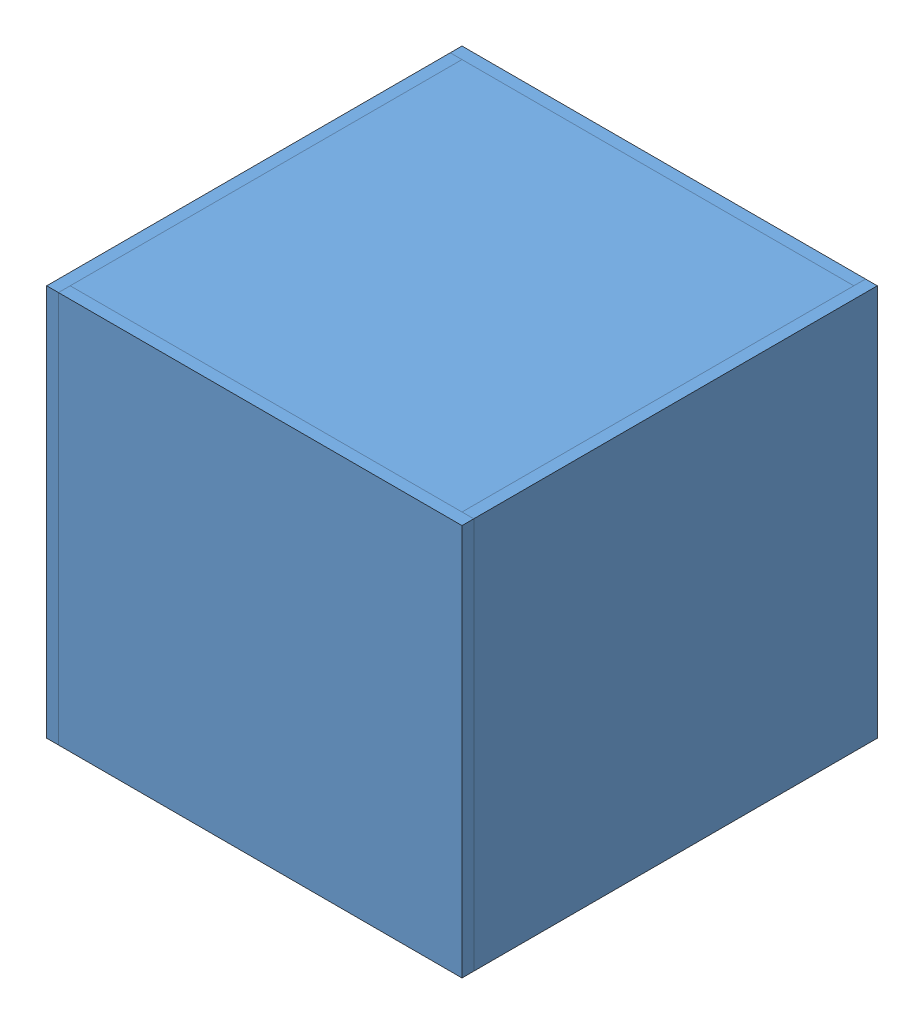
SolidWorks assembly Cube, configuration Default. Lengths in mm.
Overall size (106 102.84 106).
19 component instances, 4 part files, 40 mates.
Components (placement in the parent):
- Side.SLDPART-1: Side.SLDPART [Default] at (47.5053 44.4582 76.6376) size (100 3 100)
- Arduino-1: Arduino [Default] at (41.5053 60.1582 92.4876) size (74.8 12.1 53.3)
- 25x.5 Aluminum Hex Female Female Standoff-1: 25x.5 Aluminum Hex Female Female Standoff [Default] at (22.5053 53.8082 116.6376) x (0.377672 0 -0.92594) z (0 -1 0) size (6.35 8.06 12.7)
- 25x.5 Aluminum Hex Female Female Standoff-2: 25x.5 Aluminum Hex Female Female Standoff [Default] at (74.9053 53.8082 83.6376) x (1 0 0) z (0 -1 0) size (6.35 8.06 12.7)
- 25x.5 Aluminum Hex Female Female Standoff-3: 25x.5 Aluminum Hex Female Female Standoff [Default] at (24.1053 53.8082 68.3376) x (0.24691 0 -0.969038) z (0 -1 0) size (6.35 8.06 12.7)
- 25x.5 Aluminum Hex Female Female Standoff-4: 25x.5 Aluminum Hex Female Female Standoff [Default] at (74.9053 53.8082 111.5376) x (1 0 0) z (0 -1 0) size (6.35 8.06 12.7)
- socket head cap screw_ai-2: socket head cap screw_ai [HX-SHCS 0.112-40x0.25x0.25-N] at (22.5053 64.603 116.6376) x (0 -1 0) z (0 0 1) size (9.19 4.65 4.65)
- socket head cap screw_ai-3: socket head cap screw_ai [HX-SHCS 0.112-40x0.25x0.25-N] at (74.9053 64.603 111.5376) x (0 -1 0) z (0 0 1) size (9.19 4.65 4.65)
- socket head cap screw_ai-4: socket head cap screw_ai [HX-SHCS 0.112-40x0.25x0.25-N] at (74.9053 64.603 83.6376) x (0 -1 0) z (0 0 1) size (9.19 4.65 4.65)
- socket head cap screw_ai-5: socket head cap screw_ai [HX-SHCS 0.112-40x0.25x0.25-N] at (24.1053 64.603 68.3376) x (0 -1 0) z (0 0 1) size (9.19 4.65 4.65)
- socket head cap screw_ai-6: socket head cap screw_ai [HX-SHCS 0.112-40x0.25x0.25-N] at (74.9053 41.6134 111.5376) x (0 1 0) z (0 0 1) size (9.19 4.65 4.65)
- socket head cap screw_ai-7: socket head cap screw_ai [HX-SHCS 0.112-40x0.25x0.25-N] at (74.9053 41.6134 83.6376) x (0 1 0) z (0 0 1) size (9.19 4.65 4.65)
- socket head cap screw_ai-8: socket head cap screw_ai [HX-SHCS 0.112-40x0.25x0.25-N] at (24.1053 41.6134 68.3376) x (0 1 0) z (0 0 1) size (9.19 4.65 4.65)
- socket head cap screw_ai-9: socket head cap screw_ai [HX-SHCS 0.112-40x0.25x0.25-N] at (22.5053 41.6134 116.6376) x (0 1 0) z (0 0 1) size (9.19 4.65 4.65)
- Side.SLDPART-4: Side.SLDPART [No Holes] at (49.0053 94.4582 129.6376) x (0 1 0) z (-1 0 0) size (100 3 103)
- Side.SLDPART-5: Side.SLDPART [No Holes] at (46.0053 94.4582 23.6376) x (0 1 0) z (1 0 0) size (100 3 103)
- Side.SLDPART-6: Side.SLDPART [No Holes] at (100.5053 94.4582 75.1376) x (0 1 0) z (0 0 1) size (100 3 103)
- Side.SLDPART-7: Side.SLDPART [No Holes] at (-5.4947 94.4582 78.1376) x (0 -1 0) z (0 0 1) size (100 3 103)
- Side.SLDPART-9: Side.SLDPART [No Holes Top] at (47.5053 141.4582 76.6376) size (100 3 100)
Mates (geometry in assembly coordinates):
- Concentric1: concentric anti-aligned: cylinder of Side.SLDPART-1 through (22.5053 44.4582 116.6376) axis (0 1 0) radius 1.6; cylinder of Arduino-1 through (22.5053 61.7582 116.6376) axis (0 -1 0) radius 1.6
- Concentric2: concentric anti-aligned: cylinder of Side.SLDPART-1 through (74.9053 44.4582 83.6376) axis (0 1 0) radius 1.6; cylinder of Arduino-1 through (74.9053 61.7582 83.6376) axis (0 -1 0) radius 1.6
- Concentric3: concentric anti-aligned: cylinder of Side.SLDPART-1 through (22.5053 44.4582 116.6376) axis (0 1 0) radius 1.6; cylinder of 25x.5 Aluminum Hex Female Female Standoff-1 through (22.5053 47.4582 116.6376) axis (0 -1 0) radius 1.0287
- Concentric4: concentric anti-aligned: cylinder of Side.SLDPART-1 through (74.9053 44.4582 111.5376) axis (0 1 0) radius 1.6; cylinder of 25x.5 Aluminum Hex Female Female Standoff-4 through (74.9053 47.4582 111.5376) axis (0 -1 0) radius 1.0287
- Concentric5: concentric anti-aligned: cylinder of Side.SLDPART-1 through (24.1053 44.4582 68.3376) axis (0 1 0) radius 1.6; cylinder of 25x.5 Aluminum Hex Female Female Standoff-3 through (24.1053 47.4582 68.3376) axis (0 -1 0) radius 1.0287
- Concentric6: concentric anti-aligned: cylinder of Side.SLDPART-1 through (74.9053 44.4582 83.6376) axis (0 1 0) radius 1.6; cylinder of 25x.5 Aluminum Hex Female Female Standoff-2 through (74.9053 47.4582 83.6376) axis (0 -1 0) radius 1.0287
- Coincident1: coincident anti-aligned: plane of Side.SLDPART-1 through (47.5053 47.4582 76.6376) normal (0 1 0); plane of 25x.5 Aluminum Hex Female Female Standoff-2 through (74.9053 47.4582 83.6376) normal (0 -1 0)
- Coincident2: coincident anti-aligned: plane of Side.SLDPART-1 through (47.5053 47.4582 76.6376) normal (0 1 0); plane of 25x.5 Aluminum Hex Female Female Standoff-4 through (74.9053 47.4582 111.5376) normal (0 -1 0)
- Coincident3: coincident anti-aligned: plane of Side.SLDPART-1 through (47.5053 47.4582 76.6376) normal (0 1 0); plane of 25x.5 Aluminum Hex Female Female Standoff-1 through (22.5053 47.4582 116.6376) normal (0 -1 0)
- Coincident4: coincident anti-aligned: plane of Side.SLDPART-1 through (47.5053 47.4582 76.6376) normal (0 1 0); plane of 25x.5 Aluminum Hex Female Female Standoff-3 through (24.1053 47.4582 68.3376) normal (0 -1 0)
- Coincident5: coincident anti-aligned: plane of Arduino-1 through (74.5053 60.1582 65.8376) normal (0 -1 0); plane of 25x.5 Aluminum Hex Female Female Standoff-1 through (22.5053 60.1582 116.6376) normal (0 1 0)
- Concentric7: concentric anti-aligned: cylinder of Arduino-1 through (22.5053 61.7582 116.6376) axis (0 -1 0) radius 1.6; cylinder of socket head cap screw_ai-2 through (22.5053 96.353 116.6376) axis (0 1 0) radius 2.3241
- Coincident6: coincident anti-aligned: plane of Arduino-1 through (74.5053 61.7582 65.8376) normal (0 1 0); plane of socket head cap screw_ai-2 through (24.8294 61.7582 116.6376) normal (0 -1 0)
- Concentric8: concentric anti-aligned: cylinder of Arduino-1 through (74.9053 61.7582 111.5376) axis (0 -1 0) radius 1.6; cylinder of socket head cap screw_ai-3 through (74.9053 96.353 111.5376) axis (0 1 0) radius 2.3241
- Coincident7: coincident anti-aligned: plane of Arduino-1 through (74.5053 61.7582 65.8376) normal (0 1 0); plane of socket head cap screw_ai-3 through (77.2294 61.7582 111.5376) normal (0 -1 0)
- Concentric9: concentric anti-aligned: cylinder of Arduino-1 through (74.9053 61.7582 83.6376) axis (0 -1 0) radius 1.6; cylinder of socket head cap screw_ai-4 through (74.9053 96.353 83.6376) axis (0 1 0) radius 2.3241
- Coincident8: coincident anti-aligned: plane of Arduino-1 through (74.5053 61.7582 65.8376) normal (0 1 0); plane of socket head cap screw_ai-4 through (77.2294 61.7582 83.6376) normal (0 -1 0)
- Concentric101: concentric anti-aligned: cylinder of Arduino-1 through (24.1053 61.7582 68.3376) axis (0 -1 0) radius 1.6; cylinder of socket head cap screw_ai-5 through (24.1053 96.353 68.3376) axis (0 1 0) radius 2.3241
- Coincident91: coincident anti-aligned: plane of Arduino-1 through (74.5053 61.7582 65.8376) normal (0 1 0); plane of socket head cap screw_ai-5 through (26.4294 61.7582 68.3376) normal (0 -1 0)
- Concentric11: concentric anti-aligned: cylinder of Side.SLDPART-1 through (74.9053 44.4582 111.5376) axis (0 1 0) radius 1.6; cylinder of socket head cap screw_ai-6 through (74.9053 9.8634 111.5376) axis (0 -1 0) radius 2.3241
- Coincident10: coincident anti-aligned: plane of Side.SLDPART-1 through (47.5053 44.4582 76.6376) normal (0 -1 0); plane of socket head cap screw_ai-6 through (72.5812 44.4582 111.5376) normal (0 1 0)
- Concentric12: concentric anti-aligned: cylinder of Side.SLDPART-1 through (74.9053 44.4582 83.6376) axis (0 1 0) radius 1.6; cylinder of socket head cap screw_ai-7 through (74.9053 9.8634 83.6376) axis (0 -1 0) radius 2.3241
- Coincident11: coincident anti-aligned: plane of Side.SLDPART-1 through (47.5053 44.4582 76.6376) normal (0 -1 0); plane of socket head cap screw_ai-7 through (72.5812 44.4582 83.6376) normal (0 1 0)
- Concentric13: concentric anti-aligned: cylinder of Side.SLDPART-1 through (24.1053 44.4582 68.3376) axis (0 1 0) radius 1.6; cylinder of socket head cap screw_ai-8 through (24.1053 9.8634 68.3376) axis (0 -1 0) radius 2.3241
- Coincident12: coincident anti-aligned: plane of Side.SLDPART-1 through (47.5053 44.4582 76.6376) normal (0 -1 0); plane of socket head cap screw_ai-8 through (21.7812 44.4582 68.3376) normal (0 1 0)
- Concentric14: concentric anti-aligned: cylinder of Side.SLDPART-1 through (22.5053 44.4582 116.6376) axis (0 1 0) radius 1.6; cylinder of socket head cap screw_ai-9 through (22.5053 9.8634 116.6376) axis (0 -1 0) radius 2.3241
- Coincident13: coincident anti-aligned: plane of Side.SLDPART-1 through (47.5053 44.4582 76.6376) normal (0 -1 0); plane of socket head cap screw_ai-9 through (20.1812 44.4582 116.6376) normal (0 1 0)
- Coincident103: coincident anti-aligned: line of Side.SLDPART-1 through (-2.4947 44.4582 126.6376) axis (1 0 0); line of Side.SLDPART-4 through (100.5053 44.4582 126.6376) axis (-1 0 0)
- Coincident104: coincident anti-aligned: plane of Side.SLDPART-1 through (97.5053 47.4582 126.6376) normal (0 0 1); plane of Side.SLDPART-4 through (49.0053 94.4582 126.6376) normal (0 0 -1)
- Coincident105: coincident anti-aligned: line of Side.SLDPART-1 through (-2.4947 47.4582 126.6376) axis (0 -1 0); line of Side.SLDPART-4 through (-2.4947 44.4582 126.6376) axis (0 1 0)
- Coincident107: coincident anti-aligned: line of Side.SLDPART-4 through (100.5053 144.4582 126.6376) axis (0 -1 0); line of Side.SLDPART-6 through (100.5053 44.4582 126.6376) axis (0 1 0)
- Coincident108: coincident anti-aligned: line of Side.SLDPART-1 through (97.5053 44.4582 126.6376) axis (0 0 -1); line of Side.SLDPART-6 through (97.5053 44.4582 23.6376) axis (0 0 1)
- Coincident112: coincident anti-aligned: plane of Side.SLDPART-5 through (97.5053 144.4582 26.6376) normal (1 0 0); plane of Side.SLDPART-6 through (97.5053 94.4582 75.1376) normal (-1 0 0)
- Coincident113: coincident anti-aligned: line of Side.SLDPART-1 through (97.5053 44.4582 26.6376) axis (-1 0 0); line of Side.SLDPART-5 through (-5.4947 44.4582 26.6376) axis (1 0 0)
- Coincident114: coincident aligned: line of Side.SLDPART-5 through (97.5053 144.4582 26.6376) axis (0 0 -1); line of Side.SLDPART-6 through (97.5053 144.4582 126.6376) axis (0 0 -1)
- Coincident116: coincident anti-aligned: plane of Side.SLDPART-5 through (46.0053 94.4582 26.6376) normal (0 0 1); plane of Side.SLDPART-7 through (-2.4947 44.4582 26.6376) normal (0 0 -1)
- Coincident117: coincident aligned: line of Side.SLDPART-5 through (97.5053 144.4582 26.6376) axis (-1 0 0); line of Side.SLDPART-7 through (-2.4947 144.4582 26.6376) axis (-1 0 0)
- Coincident118: coincident anti-aligned: line of Side.SLDPART-1 through (-2.4947 44.4582 26.6376) axis (0 0 1); line of Side.SLDPART-7 through (-2.4947 44.4582 129.6376) axis (0 0 -1)
- Coincident121: coincident: line of Side.SLDPART-6 through (97.5053 144.4582 126.6376) axis (0 0 -1); line of Side.SLDPART-9 through (97.5053 144.4582 126.6376) axis (0 0 -1)
- Coincident122: coincident aligned: line of Side.SLDPART-4 through (-2.4947 144.4582 126.6376) axis (1 0 0); line of Side.SLDPART-9 through (-2.4947 144.4582 126.6376) axis (1 0 0)
